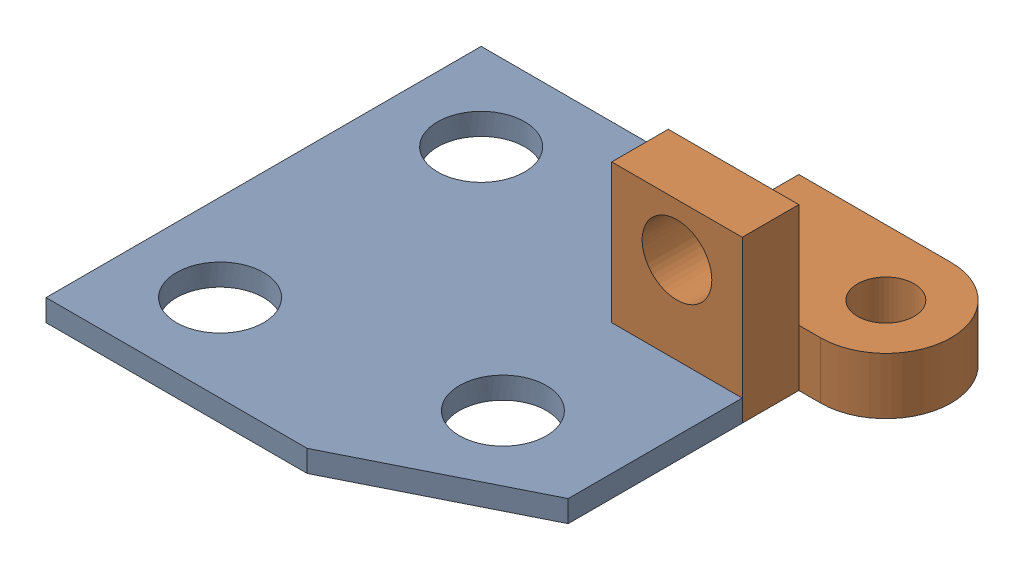
SolidWorks assembly Solidworks Class Activity 2, configuration Default. Lengths in mm.
Overall size (120 37 103).
2 component instances, 2 part files, 6 mates.
Components (placement in the parent):
- Model1-1: Model1 [Default] at (27.1641 0 -68.8594) size (100 5 100)
- Model3-1: Model3 [Default] at (75.6373 0 -92.9) x (0 0 1) z (-1 0 0) size (43 37 50)
Mates (geometry in assembly coordinates):
- Coincident1: coincident aligned: plane of Model1-1 through (0 5 0) normal (0 0 1)
- Coincident2: coincident anti-aligned: plane of Model1-1 through (0 5 -100) normal (-1 0 0)
- Coincident3: coincident anti-aligned: plane of Model1-1 through (27.1641 0 -68.8594) normal (0 -1 0)
- Coincident4: coincident: plane of Model1-1 through (100 5 -60) normal (0 0 -1); plane of Model3-1 through (75.6373 0 -60) normal (0 0 1)
- Coincident5: coincident: plane of Model1-1 through (70 5 -60) normal (1 0 0); plane of Model3-1 through (70 13 -102.998) normal (-1 0 0)
- Coincident6: coincident aligned: plane of Model1-1 through (27.1641 0 -68.8594) normal (0 -1 0); plane of Model3-1 through (105 0 -87.998) normal (0 -1 0)
